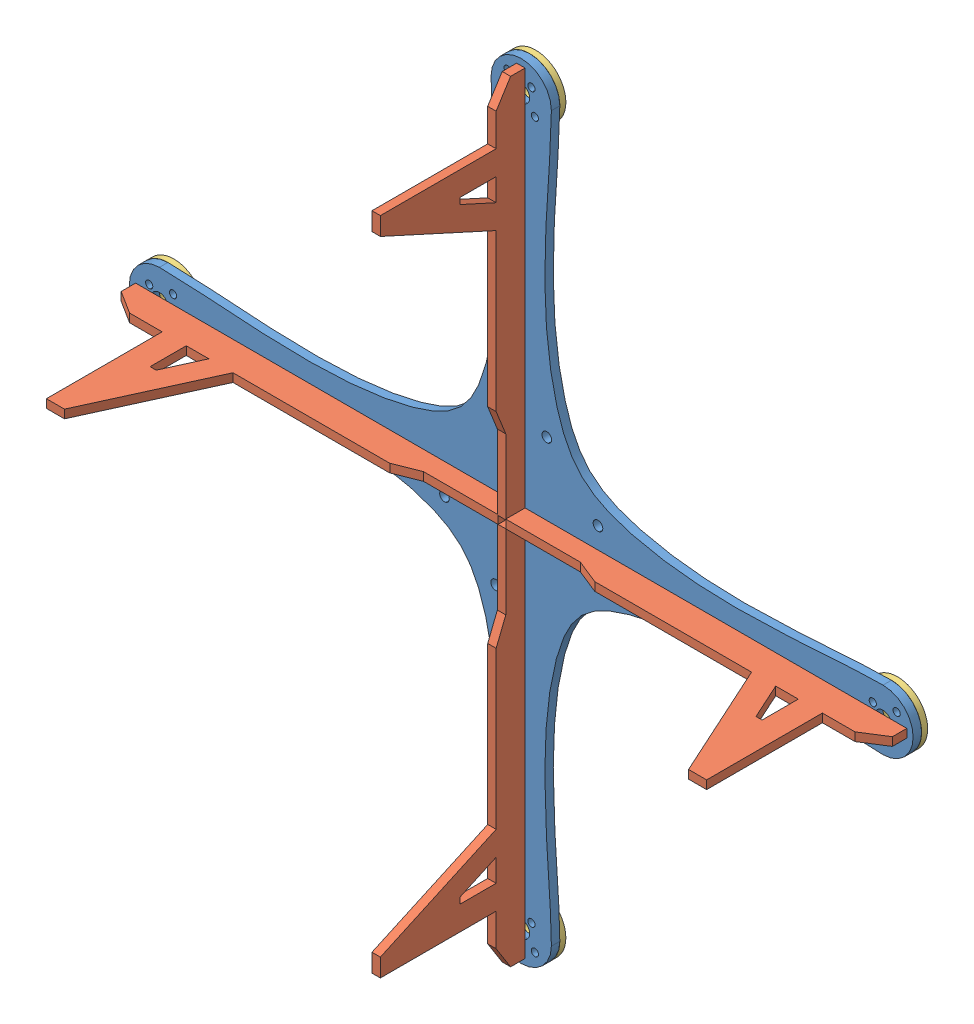
SolidWorks assembly Drone_project_318, configuration Default. Lengths in mm.
Overall size (325 325 66).
7 component instances, 3 part files, 6 mates.
Components (placement in the parent):
- Drone_project_318-1: Drone_project_318 [Default] at (56.3714 183.9099 274.0145) size (325 325 3.5)
- Drone_leg_project_318-1: Drone_leg_project_318 [Default] at (57.9714 151.41 277.5145) x (0 -1 0) z (-1 0 0) size (319.74 63.5 3.5)
- Drone_project_spacer_318-2: Drone_project_spacer_318 [Default] at (56.3714 483.9099 271.5145) size (25 25 2.5)
- Drone_project_spacer_318-3: Drone_project_spacer_318 [Default] at (-243.6286 183.9099 271.5145) x (0 1 0) z (0 0 1) size (25 25 2.5)
- Drone_project_spacer_318-4: Drone_project_spacer_318 [Default] at (56.3714 -116.0901 271.5145) x (-1 0 0) z (0 0 1) size (25 25 2.5)
- Drone_project_spacer_318-5: Drone_project_spacer_318 [Default] at (356.3714 183.9099 271.5145) x (0 -1 0) z (0 0 1) size (25 25 2.5)
- Drone_leg_project_318-2: Drone_leg_project_318 [Default] at (23.8715 182.3099 277.5145) x (-1 0 0) z (0 1 0) size (319.74 63.5 3.5)
Mates (geometry in assembly coordinates):
- Coincident3: coincident: plane of Drone_project_318-1 through (56.3714 183.9099 274.0145) normal (0 0 -1); plane of Drone_leg_project_318-1 through (54.4714 101.8746 274.0145) normal (0 0 -1)
- Coincident4: coincident: plane of Drone_project_318-1 through (57.9714 183.9099 277.5145) normal (-1 0 0); plane of Drone_leg_project_318-1 through (57.9714 151.41 277.5145) normal (1 0 0)
- Coincident5: coincident: plane of Drone_project_318-1 through (56.3714 47.039 277.5145) normal (0 1 0); plane of Drone_leg_project_318-1 through (54.4714 47.039 274.0145) normal (0 -1 0)
- Coincident12: coincident: plane of Drone_project_318-1 through (56.3714 183.9099 274.0145) normal (0 0 -1); plane of Drone_project_spacer_318-2 through (56.3714 333.9099 274.0145) normal (0 0 1)
- Concentric1: concentric: circle of Drone_project_318-1; circle of Drone_project_spacer_318-2
- Concentric2: concentric: cylinder of Drone_project_318-1 through (62.0282 328.2531 277.5145) axis (0 0 -1) radius 1.5; cylinder of Drone_project_spacer_318-2 through (62.0282 328.2531 274.0145) axis (0 0 -1) radius 1.5
